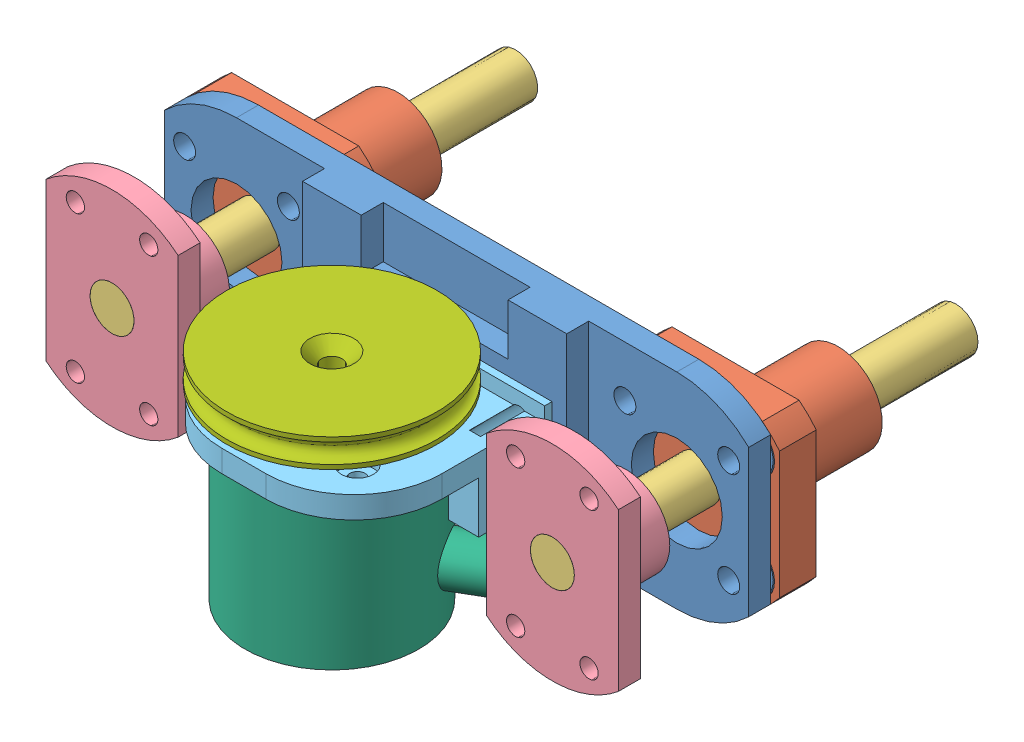
SolidWorks assembly BigRobotEncoderLeftBlock, configuration Default. Lengths in mm.
Overall size (99.6 39.6 73.98).
10 component instances, 7 part files, 23 mates.
Components (placement in the parent):
- LMK06-Support-Link-1: LMK06-Support-Link [Default] at (19.9572 45.5763 64.5681) size (80.24 28 9.3)
- LMK6UU-1: LMK6UU [Default] at (-10.0428 45.5763 44.0681) x (0 0 1) z (-0.707107 -0.707107 0) size (19 28 28)
- LMK6UU-2: LMK6UU [Default] at (49.9572 45.5763 44.0681) x (0 0 1) z (-0.707107 -0.707107 0) size (19 28 28)
- LinearShaft6x55mm-1: LinearShaft6x55mm [Default] at (-10.0428 45.5763 28.0252) x (0.980312 -0.197453 0) z (0 0 1) size (6 6 55)
- LinearShaft6x55mm-2: LinearShaft6x55mm [Default] at (49.9572 45.5763 28.0252) size (6 6 55)
- KH06-10PP-Axis-Support-1: KH06-10PP-Axis-Support [Default] at (-10.0428 45.5763 83.0252) x (1 0 0) z (0 0 -1) size (18 28 10)
- KH06-10PP-Axis-Support-2: KH06-10PP-Axis-Support [Default] at (49.9572 45.5763 83.0252) x (-1 0 0) z (0 0 -1) size (18 28 10)
- Support-BigRobot-Coders-Scancon-2RMHF-For-LinearBall-1: Support-BigRobot-Coders-Scancon-2RMHF-For-LinearBall [Default] at (19.9572 43.5763 95.0681) x (-1 0 0) z (0 0 -1) size (32 16 29)
- Coders-Scancon-2RMHF-1: Coders-Scancon-2RMHF [Défaut] at (19.9572 26.2763 83.0681) x (0 1 0) z (-0.5 0 -0.866025) size (24.4 36.85 23.7)
- Wheel-Free-With-Axis-27x5mm-1: Wheel-Free-With-Axis-27x5mm [Défaut] at (19.9572 53.6063 83.0681) x (-0.408581 0 0.912722) z (0.912722 0 0.408581) size (28.66 9.86 28.66)
Mates (geometry in assembly coordinates):
- Coincident1: coincident anti-aligned: plane of LMK06-Support-Link-1 through (-10.0428 45.5763 63.0681) normal (0 0 -1); plane of LMK6UU-1 through (-10.0428 45.5763 63.0681) normal (0 0 1)
- Concentric1: concentric aligned: cylinder of LMK06-Support-Link-1 through (-17.1139 38.5052 59.7681) axis (0 0 1) radius 1.5; cylinder of LMK6UU-1 through (-17.1139 38.5052 63.0681) axis (0 0 1) radius 1.7
- Concentric2: concentric aligned: cylinder of LMK06-Support-Link-1 through (-2.9717 52.6474 59.7681) axis (0 0 1) radius 1.5; cylinder of LMK6UU-1 through (-2.9717 52.6474 63.0681) axis (0 0 1) radius 1.7
- Coincident2: coincident anti-aligned: plane of LMK06-Support-Link-1 through (-10.0428 45.5763 63.0681) normal (0 0 -1); plane of LMK6UU-2 through (49.9572 45.5763 63.0681) normal (0 0 1)
- Concentric3: concentric aligned: cylinder of LMK06-Support-Link-1 through (57.0283 52.6474 59.7681) axis (0 0 1) radius 1.5; cylinder of LMK6UU-2 through (57.0283 52.6474 63.0681) axis (0 0 1) radius 1.7
- Concentric4: concentric aligned: cylinder of LMK06-Support-Link-1 through (42.8861 38.5052 59.7681) axis (0 0 1) radius 1.5; cylinder of LMK6UU-2 through (42.8861 38.5052 63.0681) axis (0 0 1) radius 1.7
- Concentric5: concentric anti-aligned: cylinder of LMK6UU-1 through (-10.0428 45.5763 63.0681) axis (0 0 1) radius 3; cylinder of LinearShaft6x55mm-1 through (-10.0428 45.5763 83.0252) axis (0 0 -1) radius 3
- Concentric6: concentric anti-aligned: cylinder of LMK6UU-2 through (49.9572 45.5763 63.0681) axis (0 0 1) radius 3; cylinder of LinearShaft6x55mm-2 through (49.9572 45.5763 83.0252) axis (0 0 -1) radius 3
- Coincident3: coincident aligned: plane of LinearShaft6x55mm-1 through (-10.0428 45.5763 28.0252) normal (0 0 -1); plane of LinearShaft6x55mm-2 through (49.9572 45.5763 28.0252) normal (0 0 -1)
- Concentric7: concentric anti-aligned: cylinder of LinearShaft6x55mm-1 through (-10.0428 45.5763 83.0252) axis (0 0 -1) radius 3; cylinder of KH06-10PP-Axis-Support-1 through (-10.0428 45.5763 80.0252) axis (0 0 1) radius 3
- Parallel1: parallel aligned: plane of LMK06-Support-Link-1 through (-19.8428 55.5743 66.0681) normal (-1 0 0); plane of KH06-10PP-Axis-Support-1 through (-19.0428 34.8525 80.0252) normal (-1 0 0)
- Coincident7: coincident aligned: plane of LinearShaft6x55mm-1 through (-10.0428 45.5763 83.0252) normal (0 0 1); plane of KH06-10PP-Axis-Support-1 through (-10.0428 45.5763 83.0252) normal (0 0 1)
- Concentric8: concentric anti-aligned: cylinder of LinearShaft6x55mm-2 through (49.9572 45.5763 83.0252) axis (0 0 -1) radius 3; cylinder of KH06-10PP-Axis-Support-2 through (49.9572 45.5763 80.0252) axis (0 0 1) radius 3
- Coincident8: coincident aligned: plane of LinearShaft6x55mm-2 through (49.9572 45.5763 83.0252) normal (0 0 1); plane of KH06-10PP-Axis-Support-2 through (49.9572 45.5763 83.0252) normal (0 0 1)
- Parallel2: parallel aligned: plane of LMK06-Support-Link-1 through (59.7572 55.5743 66.0681) normal (1 0 0); plane of KH06-10PP-Axis-Support-2 through (58.9572 56.3001 80.0252) normal (1 0 0)
- Coincident9: coincident anti-aligned: plane of LMK06-Support-Link-1 through (-10.0428 45.5763 66.0681) normal (0 0 1); plane of Support-BigRobot-Coders-Scancon-2RMHF-For-LinearBall-1 through (19.9572 43.5763 66.0681) normal (0 0 -1)
- Concentric9: concentric aligned: cylinder of LMK06-Support-Link-1 through (7.4572 47.5763 69.0681) axis (0 0 -1) radius 1.5; circle of Support-BigRobot-Coders-Scancon-2RMHF-For-LinearBall-1
- Concentric10: concentric aligned: circle of LMK06-Support-Link-1; cylinder of Support-BigRobot-Coders-Scancon-2RMHF-For-LinearBall-1 through (32.4572 37.5763 76.0681) axis (0 0 -1) radius 1.25
- Coincident10: coincident anti-aligned: plane of Support-BigRobot-Coders-Scancon-2RMHF-For-LinearBall-1 through (19.9572 45.5763 83.0681) normal (0 -1 0); plane of Coders-Scancon-2RMHF-1 through (25.8462 45.5763 79.6681) normal (0 1 0)
- Concentric11: concentric aligned: cylinder of Support-BigRobot-Coders-Scancon-2RMHF-For-LinearBall-1 through (19.9572 48.5763 83.0681) axis (0 -1 0) radius 7.15; cylinder of Coders-Scancon-2RMHF-1 through (19.9572 26.2763 83.0681) axis (0 -1 0) radius 6.8
- Concentric12: concentric anti-aligned: cylinder of Support-BigRobot-Coders-Scancon-2RMHF-For-LinearBall-1 through (19.9572 48.5763 73.5681) axis (0 -1 0) radius 1.05; cylinder of Coders-Scancon-2RMHF-1 through (19.9572 41.5763 73.5681) axis (0 1 0) radius 1
- Concentric13: concentric anti-aligned: cylinder of Coders-Scancon-2RMHF-1 through (19.9572 36.6763 83.0681) axis (0 1 0) radius 2; cylinder of Wheel-Free-With-Axis-27x5mm-1 through (19.9572 35.7563 83.0681) axis (0 -1 0) radius 3
- Distance1: distance = 1 mm anti-aligned: plane of Coders-Scancon-2RMHF-1 through (19.9572 50.6763 83.0681) normal (0 1 0); plane of Wheel-Free-With-Axis-27x5mm-1 through (14.1023 51.6763 96.1474) normal (0 -1 0)
